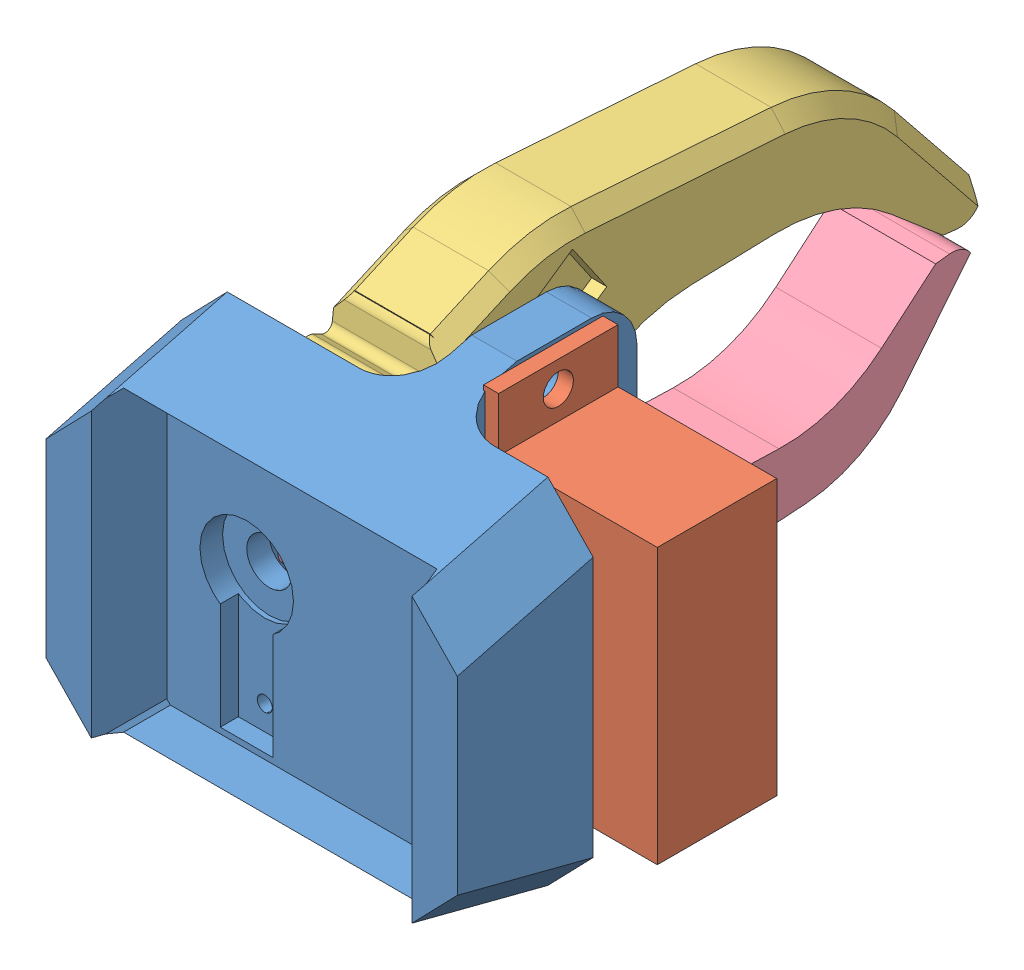
SolidWorks assembly 爪子, configuration 默认. Lengths in mm.
Overall size (29.28 28.31 50.35).
4 component instances, 4 part files, 6 mates.
Components (placement in the parent):
- 横滚-1: 横滚 [默认] at (-8.0086 -8.3265 23.9745) size (27.28 25.74 21.41)
- 2.4g舵机-1: 2.4g舵机 [默认] at (4.4614 -5.0075 18.786) x (0 0 1) z (-1 0 0) size (7.91 25 19.8)
- 爪子1-1: 爪子1 [默认] at (7.4614 -5.2587 19.5969) x (0 0.070677 0.997499) z (-1 0 0) size (40.46 15.35 7)
- 爪子2-1: 爪子2 [默认] at (-35.5504 7.9523 19.5737) x (0 -0.068682 0.997639) z (1 0 0) size (40.56 14.12 7)
Mates (geometry in assembly coordinates):
- Coincident1: coincident anti-aligned: circle of 2.4g舵机-1; circle of 横滚-1
- Parallel1: parallel anti-aligned: plane of 横滚-1 through (-5.0086 10.8667 18.666) normal (0 0 1); plane of 2.4g舵机-1 through (4.4614 -5.0075 18.786) normal (0 0 -1)
- Concentric1: concentric aligned: cylinder of 2.4g舵机-1 through (-13.2986 6.3257 22.741) axis (1 0 0) radius 1.9516; cylinder of 爪子1-1 through (-17.2986 6.3257 22.741) axis (1 0 0) radius 3.1
- Coincident3: coincident anti-aligned: plane of 2.4g舵机-1 through (-10.2986 10.6167 26.696) normal (-1 0 0); plane of 爪子1-1 through (-10.2986 6.3257 22.741) normal (1 0 0)
- Coincident6: coincident anti-aligned: circle of 横滚-1; cylinder of 爪子2-1 through (-10.7904 -3.6258 22.741) axis (-1 0 0) radius 1.5
- Coincident7: coincident anti-aligned: plane of 横滚-1 through (-17.7904 -0.0018 5.2542) normal (1 0 0); plane of 爪子2-1 through (-17.7904 -3.6258 22.741) normal (-1 0 0)
